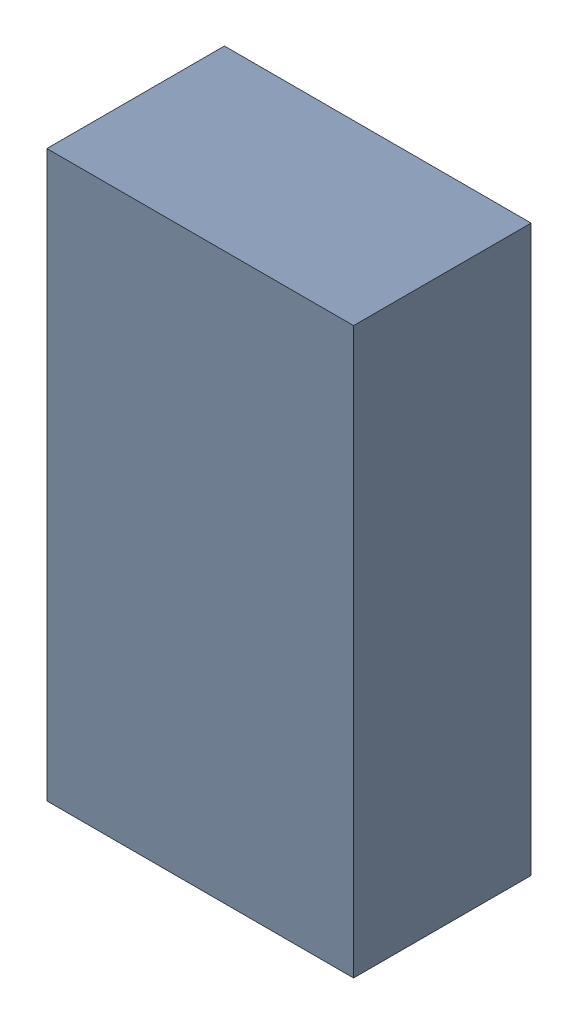
SolidWorks assembly L2_TDA4, configuration Standard. Lengths in mm.
Overall size (0.95 1.75 0.55).
2 component instances, 1 part files, 0 mates.
Components (placement in the parent):
- 885542784-1: 885542784 [Standard] at (-1.88 -59.92 0) size (0.95 1.75 0.55)
  - Extruded_22-1: Extruded_22 [Standard] at origin size (0.95 1.75 0.55)
